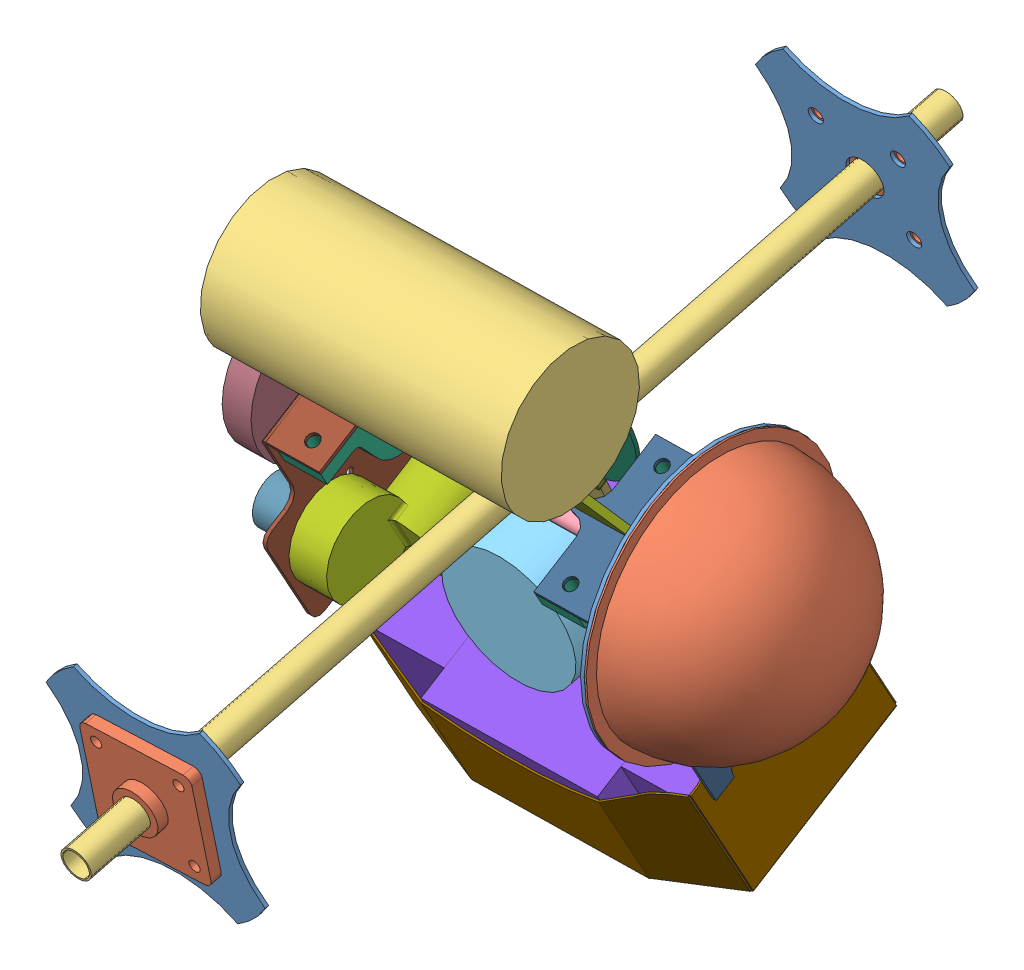
SolidWorks assembly integrated, configuration Default. Lengths in mm.
Overall size (475.58 540.92 801.49).
124 component instances, 31 part files, 95 mates.
Components (placement in the parent):
- whole_shell-1: whole_shell [Default] x (0.998835 -0.023991 -0.04186) z (0.036124 -0.203278 0.978455) size (1237.57 1237.01 762) (hidden)
  - frame1-1: frame1 [Default] x (0.840513 0.541791 0) z (-0.541791 0.840513 0) size (896.02 758.6 894.17)
    - sphere_outline-1: sphere_outline [Default] at origin size (762 758.6 762) (hidden)
    - rib-1: rib [Default] x (-1 0 0) z (0 1 0) size (381.83 596.96 365.18)
    - waist-1: waist [Default] x (-1 0 0) z (0 1 0) size (743.4 741.73 3.17)
    - axle_frame-1: axle_frame [Default] at (0 -6.0987 0) x (-1 0 0) z (0 1 0) size (203.2 203.2 44.45)
    - inside_rib-1: inside_rib [Default] x (1 0 0) z (0 1 0) size (379.15 205.09 365.17)
    - outside_rib-1: outside_rib [Default] x (1 0 0) z (0 1 0) size (373.79 201.22 360.01)
    - outside_rib-2: outside_rib [Default] x (0.809017 0 -0.587785) z (0 1 0) size (373.79 201.22 360.01)
    - outside_rib-3: outside_rib [Default] x (0.309017 0 -0.951057) z (0 1 0) size (373.79 201.22 360.01)
    - outside_rib-4: outside_rib [Default] x (-0.309017 0 -0.951057) z (0 1 0) size (373.79 201.22 360.01)
    - outside_rib-5: outside_rib [Default] x (-0.809017 0 -0.587785) z (0 1 0) size (373.79 201.22 360.01)
    - outside_rib-6: outside_rib [Default] x (-1 0 0) z (0 1 0) size (373.79 201.22 360.01)
    - outside_rib-7: outside_rib [Default] x (-0.809017 0 0.587785) z (0 1 0) size (373.79 201.22 360.01)
    - outside_rib-8: outside_rib [Default] x (-0.309017 0 0.951057) z (0 1 0) size (373.79 201.22 360.01)
    - outside_rib-9: outside_rib [Default] x (0.309017 0 0.951057) z (0 1 0) size (373.79 201.22 360.01)
    - inside_rib-2: inside_rib [Default] x (0.809017 0 -0.587785) z (0 1 0) size (379.15 205.09 365.17)
    - inside_rib-3: inside_rib [Default] x (0.309017 0 -0.951057) z (0 1 0) size (379.15 205.09 365.17)
    - inside_rib-4: inside_rib [Default] x (-0.309017 0 -0.951057) z (0 1 0) size (379.15 205.09 365.17)
    - inside_rib-5: inside_rib [Default] x (-0.809017 0 -0.587785) z (0 1 0) size (379.15 205.09 365.17)
    - inside_rib-6: inside_rib [Default] x (-1 0 0) z (0 1 0) size (379.15 205.09 365.17)
    - inside_rib-7: inside_rib [Default] x (-0.809017 0 0.587785) z (0 1 0) size (379.15 205.09 365.17)
    - inside_rib-8: inside_rib [Default] x (-0.309017 0 0.951057) z (0 1 0) size (379.15 205.09 365.17)
    - inside_rib-9: inside_rib [Default] x (0.309017 0 0.951057) z (0 1 0) size (379.15 205.09 365.17)
    - outside_rib-10: outside_rib [Default] x (0.809017 0 0.587785) z (0 1 0) size (373.79 201.22 360.01)
    - inside_rib-10: inside_rib [Default] x (0.809017 0 0.587785) z (0 1 0) size (379.15 205.09 365.17)
    - inside_rib-21: inside_rib [short] x (0.951057 0 -0.309017) z (0 1 0) size (304.88 133.31 293.67)
    - inside_rib-22: inside_rib [short] x (0.587785 0 -0.809017) z (0 1 0) size (304.88 133.31 293.67)
    - inside_rib-23: inside_rib [short] x (0 0 -1) z (0 1 0) size (304.88 133.31 293.67)
    - inside_rib-24: inside_rib [short] x (-0.587785 0 -0.809017) z (0 1 0) size (304.88 133.31 293.67)
    - inside_rib-25: inside_rib [short] x (-0.951057 0 -0.309017) z (0 1 0) size (304.88 133.31 293.67)
    - inside_rib-26: inside_rib [short] x (-0.951057 0 0.309017) z (0 1 0) size (304.88 133.31 293.67)
    - inside_rib-27: inside_rib [short] x (-0.587785 0 0.809017) z (0 1 0) size (304.88 133.31 293.67)
    - inside_rib-28: inside_rib [short] x (0 0 1) z (0 1 0) size (304.88 133.31 293.67)
    - inside_rib-29: inside_rib [short] x (0.587785 0 0.809017) z (0 1 0) size (304.88 133.31 293.67)
    - inside_rib-30: inside_rib [short] x (0.951057 0 0.309017) z (0 1 0) size (304.88 133.31 293.67)
    - outside_rib-21: outside_rib [short] x (0.951057 0 -0.309017) z (0 1 0) size (304.88 133.31 293.67)
    - outside_rib-22: outside_rib [short] x (0.587785 0 -0.809017) z (0 1 0) size (304.88 133.31 293.67)
    - outside_rib-23: outside_rib [short] x (0 0 -1) z (0 1 0) size (304.88 133.31 293.67)
    - outside_rib-24: outside_rib [short] x (-0.587785 0 -0.809017) z (0 1 0) size (304.88 133.31 293.67)
    - outside_rib-25: outside_rib [short] x (-0.951057 0 -0.309017) z (0 1 0) size (304.88 133.31 293.67)
    - outside_rib-26: outside_rib [short] x (-0.951057 0 0.309017) z (0 1 0) size (304.88 133.31 293.67)
    - outside_rib-27: outside_rib [short] x (-0.587785 0 0.809017) z (0 1 0) size (304.88 133.31 293.67)
    - outside_rib-28: outside_rib [short] x (0 0 1) z (0 1 0) size (304.88 133.31 293.67)
    - outside_rib-29: outside_rib [short] x (0.587785 0 0.809017) z (0 1 0) size (304.88 133.31 293.67)
    - outside_rib-30: outside_rib [short] x (0.951057 0 0.309017) z (0 1 0) size (304.88 133.31 293.67)
  - frame1-2: frame1 [Default] x (-0.840513 -0.541791 0) z (-0.541791 0.840513 0) size (896.02 758.6 894.17)
    - sphere_outline-1: sphere_outline [Default] at origin size (762 758.6 762) (hidden)
    - rib-1: rib [Default] x (-1 0 0) z (0 1 0) size (381.83 596.96 365.18)
    - waist-1: waist [Default] x (-1 0 0) z (0 1 0) size (743.4 741.73 3.17)
    - axle_frame-1: axle_frame [Default] at (0 -6.0987 0) x (-1 0 0) z (0 1 0) size (203.2 203.2 44.45)
    - inside_rib-1: inside_rib [Default] x (1 0 0) z (0 1 0) size (379.15 205.09 365.17)
    - outside_rib-1: outside_rib [Default] x (1 0 0) z (0 1 0) size (373.79 201.22 360.01)
    - outside_rib-2: outside_rib [Default] x (0.809017 0 -0.587785) z (0 1 0) size (373.79 201.22 360.01)
    - outside_rib-3: outside_rib [Default] x (0.309017 0 -0.951057) z (0 1 0) size (373.79 201.22 360.01)
    - outside_rib-4: outside_rib [Default] x (-0.309017 0 -0.951057) z (0 1 0) size (373.79 201.22 360.01)
    - outside_rib-5: outside_rib [Default] x (-0.809017 0 -0.587785) z (0 1 0) size (373.79 201.22 360.01)
    - outside_rib-6: outside_rib [Default] x (-1 0 0) z (0 1 0) size (373.79 201.22 360.01)
    - outside_rib-7: outside_rib [Default] x (-0.809017 0 0.587785) z (0 1 0) size (373.79 201.22 360.01)
    - outside_rib-8: outside_rib [Default] x (-0.309017 0 0.951057) z (0 1 0) size (373.79 201.22 360.01)
    - outside_rib-9: outside_rib [Default] x (0.309017 0 0.951057) z (0 1 0) size (373.79 201.22 360.01)
    - inside_rib-2: inside_rib [Default] x (0.809017 0 -0.587785) z (0 1 0) size (379.15 205.09 365.17)
    - inside_rib-3: inside_rib [Default] x (0.309017 0 -0.951057) z (0 1 0) size (379.15 205.09 365.17)
    - inside_rib-4: inside_rib [Default] x (-0.309017 0 -0.951057) z (0 1 0) size (379.15 205.09 365.17)
    - inside_rib-5: inside_rib [Default] x (-0.809017 0 -0.587785) z (0 1 0) size (379.15 205.09 365.17)
    - inside_rib-6: inside_rib [Default] x (-1 0 0) z (0 1 0) size (379.15 205.09 365.17)
    - inside_rib-7: inside_rib [Default] x (-0.809017 0 0.587785) z (0 1 0) size (379.15 205.09 365.17)
    - inside_rib-8: inside_rib [Default] x (-0.309017 0 0.951057) z (0 1 0) size (379.15 205.09 365.17)
    - inside_rib-9: inside_rib [Default] x (0.309017 0 0.951057) z (0 1 0) size (379.15 205.09 365.17)
    - outside_rib-10: outside_rib [Default] x (0.809017 0 0.587785) z (0 1 0) size (373.79 201.22 360.01)
    - inside_rib-10: inside_rib [Default] x (0.809017 0 0.587785) z (0 1 0) size (379.15 205.09 365.17)
    - inside_rib-21: inside_rib [short] x (0.951057 0 -0.309017) z (0 1 0) size (304.88 133.31 293.67)
    - inside_rib-22: inside_rib [short] x (0.587785 0 -0.809017) z (0 1 0) size (304.88 133.31 293.67)
    - inside_rib-23: inside_rib [short] x (0 0 -1) z (0 1 0) size (304.88 133.31 293.67)
    - inside_rib-24: inside_rib [short] x (-0.587785 0 -0.809017) z (0 1 0) size (304.88 133.31 293.67)
    - inside_rib-25: inside_rib [short] x (-0.951057 0 -0.309017) z (0 1 0) size (304.88 133.31 293.67)
    - inside_rib-26: inside_rib [short] x (-0.951057 0 0.309017) z (0 1 0) size (304.88 133.31 293.67)
    - inside_rib-27: inside_rib [short] x (-0.587785 0 0.809017) z (0 1 0) size (304.88 133.31 293.67)
    - inside_rib-28: inside_rib [short] x (0 0 1) z (0 1 0) size (304.88 133.31 293.67)
    - inside_rib-29: inside_rib [short] x (0.587785 0 0.809017) z (0 1 0) size (304.88 133.31 293.67)
    - inside_rib-30: inside_rib [short] x (0.951057 0 0.309017) z (0 1 0) size (304.88 133.31 293.67)
    - outside_rib-21: outside_rib [short] x (0.951057 0 -0.309017) z (0 1 0) size (304.88 133.31 293.67)
    - outside_rib-22: outside_rib [short] x (0.587785 0 -0.809017) z (0 1 0) size (304.88 133.31 293.67)
    - outside_rib-23: outside_rib [short] x (0 0 -1) z (0 1 0) size (304.88 133.31 293.67)
    - outside_rib-24: outside_rib [short] x (-0.587785 0 -0.809017) z (0 1 0) size (304.88 133.31 293.67)
    - outside_rib-25: outside_rib [short] x (-0.951057 0 -0.309017) z (0 1 0) size (304.88 133.31 293.67)
    - outside_rib-26: outside_rib [short] x (-0.951057 0 0.309017) z (0 1 0) size (304.88 133.31 293.67)
    - outside_rib-27: outside_rib [short] x (-0.587785 0 0.809017) z (0 1 0) size (304.88 133.31 293.67)
    - outside_rib-28: outside_rib [short] x (0 0 1) z (0 1 0) size (304.88 133.31 293.67)
    - outside_rib-29: outside_rib [short] x (0.587785 0 0.809017) z (0 1 0) size (304.88 133.31 293.67)
    - outside_rib-30: outside_rib [short] x (0.951057 0 0.309017) z (0 1 0) size (304.88 133.31 293.67)
- hub_flange-1: hub_flange [Default] at (-11.8884 66.8994 -322.0129) x (0.999347 0.007348 -0.035369) z (0.036124 -0.203278 0.978455) size (165.1 165.1 3.17)
- flange_bearing-1: flange_bearing [Default] at (-12.0031 67.5448 -325.1194) x (0.999347 0.007348 -0.035369) z (0 0.979094 0.20341) size (95.25 19.05 95.25)
- hub_flange-2: hub_flange [Default] at (12.0031 -67.5448 325.1194) x (0.999347 0.007348 -0.035369) z (0.036124 -0.203278 0.978455) size (165.1 165.1 3.17)
- flange_bearing-2: flange_bearing [Default] at (12.0031 -67.5448 325.1194) x (0.999347 0.007348 -0.035369) z (0 -0.979094 -0.20341) size (95.25 19.05 95.25)
- axle-1: axle [Default] x (0.998835 -0.023991 -0.04186) z (-0.031984 -0.978827 -0.202174) size (25.4 812.8 25.4)
- small_axle-1: small_axle [Default] x (-0.036124 0.203278 -0.978455) z (0.998835 -0.023991 -0.04186) size (15.88 15.88 327.03)
- drive_motor-1: drive_motor [Default] at (15.4437 -68.5896 -47.269) x (0.599108 0.788047 0.141601) z (0.036124 -0.203278 0.978455) size (112 132 107.2)
- pillow_block-1: pillow_block [Default] at (105.3435 26.4021 12.2055) x (0.024368 -0.497968 0.866853) z (0.998835 -0.023991 -0.04186) size (127 59.45 36.51)
- pillow_block-2: pillow_block [Default] at (-112.0809 31.6245 21.3176) x (0.024368 -0.497968 0.866853) z (0.998835 -0.023991 -0.04186) size (127 59.45 36.51)
- steering_motor-2: steering_motor [Default] at (-144.0481 -97.9785 15.4513) x (-0.041642 -0.866863 -0.496804) z (-0.998835 0.023991 0.04186) size (101.85 177.8 87.5)
- battery_module-2: battery_module [Default] at (-5.7974 -187.0692 -31.1163) x (0.998835 -0.023991 -0.04186) z (-0.024368 0.497968 -0.866853) size (284.35 141.22 201.17)
  - battery-1: battery [for_assembly] at origin size (149.22 101.6 66.04)
  - battery-4: battery [for_assembly] at (0 0 66.04) size (149.22 101.6 66.04)
  - battery-5: battery [for_assembly] at (0 0 132.08) size (149.22 101.6 66.04)
  - battery-8: battery [for_assembly] at (107.6325 0 66.04) x (0 0 -1) z (1 0 0) size (149.22 101.6 66.04)
  - battery-9: battery [for_assembly] at (-107.6325 0 66.04) x (0 0 1) z (-1 0 0) size (149.22 101.6 66.04)
  - battery_tray-1: battery_tray [Default] at (0 101.6 66.04) x (-1 0 0) z (0 1 0) size (284.35 201.17 141.22)
- tray_bracket-1: tray_bracket [Default] at (105.3435 26.4021 12.2055) x (-0.998835 0.023991 0.04186) z (0.024368 -0.497968 0.866853) size (78.58 215.9 127)
- steering_bracket-3: steering_bracket [Default] at (-112.0809 31.6245 21.3176) x (-0.998835 0.023991 0.04186) z (0.024368 -0.497968 0.866853) size (69.06 215.9 165.1)
- motor_plate-1: motor_plate [Default] at (15.4437 -68.5896 -47.269) x (-0.599108 -0.788047 -0.141601) z (-0.036124 0.203278 -0.978455) size (138.65 111.84 6.35)
- driveshaft-1: driveshaft [Default] at (-11.8884 66.8994 -322.0129) x (0.999347 0.007348 -0.035369) z (0.036124 -0.203278 0.978455) size (38.1 38.1 279.4) (hidden)
- tsprock_40-1: tsprock_40 [Default] at (-164.3369 3.9473 6.8872) x (0.041034 -0.033955 0.998581) z (-0.998835 0.023991 0.04186) size (121.29 121.29 24.38)
- tsprock_10-1: tsprock_10 [Default] at (-166.3741 -97.4423 16.3869) x (-0.047046 -0.676787 -0.734674) z (-0.998835 0.023991 0.04186) size (41.68 41.68 24.38)
- cog_27t-1: cog_27t [Default] at (-2.5088 14.1176 -67.9537) x (0.99934 0.003712 -0.036124) z (0.036124 -0.203278 0.978455) size (88.9 88.9 3.17)
- bh_front-1: bh_front [Default] x (-0.036124 0.203278 -0.978455) z (0.994465 0.103976 -0.015113) size (822.32 411.16 9.53) (hidden)
- bh_back-1: bh_back [Default] x (-0.036124 0.203278 -0.978455) z (0.986115 -0.151549 -0.067891) size (822.32 411.16 9.53) (hidden)
- bh_pod-1: bh_pod [Default] at (12.9982 397.7954 82.1636) x (-0.999488 0.031323 0.00647) z (0.031984 0.978827 0.202174) size (127 127 25.4) (hidden)
- crossmember-1: crossmember [Default] at (105.3435 26.4021 12.2055) x (-0.998835 0.023991 0.04186) z (0.024368 -0.497968 0.866853) size (252.6 74.61 6.35)
- pot_holder-1: pot_holder [Default] at (146.5705 25.4119 10.4777) x (0.024368 -0.497968 0.866853) z (0.998835 -0.023991 -0.04186) size (50.8 44.45 1.59)
- potentiometer-1: potentiometer [Default] at (160.7216 -3.8604 -6.7357) x (0.024368 -0.497968 0.866853) z (-0.998835 0.023991 0.04186) size (26.42 26.42 39.37)
- acetal-1: acetal [Default] at (146.5705 25.4119 10.4777) x (0.024368 -0.497968 0.866853) z (0.998835 -0.023991 -0.04186) size (231.78 231.78 3.18)
- dome-1: dome [Default] at (146.5705 25.4119 10.4777) x (-0.998835 0.023991 0.04186) z (0.024368 -0.497968 0.866853) size (107.95 231.78 231.78)
- speakertube-1: speakertube [Default] at (7.404 154.1283 88.3317) x (0.024368 -0.497968 0.866853) z (-0.998835 0.023991 0.04186) size (127 127 254)
Mates (geometry in assembly coordinates):
- InPlace1: in place: plane of ?
- Coincident1: coincident aligned: plane of ?; plane of assembly
- Coincident2: coincident aligned: plane of ?; moOrthogonalPlaneRef_w of assembly
- Coincident3: coincident anti-aligned: plane of ?; moOrthogonalPlaneRef_w of assembly
- Coincident4: coincident anti-aligned: plane of ? through (-12.0031 140.1446 -310.0366) normal (-0.036124 0.203278 -0.978455); plane of flange_bearing-1 through (-59.5971 113.8242 -313.7476) normal (0.036124 -0.203278 0.978455)
- Coincident8: coincident aligned: plane of ? through (-11.8884 66.8994 -322.0129) normal (0 0.979094 0.20341); plane of flange_bearing-1 through (-12.0031 67.5448 -325.1194) normal (0 0.979094 0.20341)
- Coincident9: coincident aligned: plane of ? through (-11.8884 66.8994 -322.0129) normal (0.999347 0.007348 -0.035369); plane of flange_bearing-1 through (-12.0031 67.5448 -325.1194) normal (0.999347 0.007348 -0.035369)
- Coincident10: coincident anti-aligned: plane of hub_flange-2 through (12.0031 5.055 340.2023) normal (0.036124 -0.203278 0.978455); plane of flange_bearing-2 through (-35.5908 -114.5241 317.1165) normal (-0.036124 0.203278 -0.978455)
- Coincident11: coincident aligned: plane of flange_bearing-1 through (-12.0031 67.5448 -325.1194) normal (0.999347 0.007348 -0.035369); plane of flange_bearing-2 through (12.0031 -67.5448 325.1194) normal (0.999347 0.007348 -0.035369)
- Coincident12: coincident anti-aligned: plane of flange_bearing-1 through (-12.0031 67.5448 -325.1194) normal (0 0.979094 0.20341); plane of flange_bearing-2 through (12.0031 -67.5448 325.1194) normal (0 -0.979094 -0.20341)
- Concentric1: concentric anti-aligned: cylinder of flange_bearing-2; cylinder of axle-1
- Coincident13: coincident aligned: plane of whole_shell-1 through (0 0 0) normal (0.036124 -0.203278 0.978455); plane of axle-1 through (0 0 0) normal (0.036124 -0.203278 0.978455)
- InPlace2: in place: unknown of whole_shell-1; unknown of small_axle-1
- Coincident14: coincident aligned: plane of ?; plane of ?
- Coincident15: coincident aligned: moOrthogonalPlaneRef_w of ?; plane of ?
- Coincident16: coincident anti-aligned: moOrthogonalPlaneRef_w of ?; plane of ?
- Coincident19: coincident anti-aligned: plane of whole_shell-1 through (0 0 0) normal (0.036124 -0.203278 0.978455); plane of drive_motor-1 through (16.5906 -75.0437 -16.2031) normal (-0.036124 0.203278 -0.978455)
- Distance1: distance = 19.05 mm anti-aligned: plane of whole_shell-1 through (0 0 0) normal (0.998835 -0.023991 -0.04186); plane of drive_motor-1 through (15.4437 -68.5896 -47.269) normal (-0.998835 0.023991 0.04186)
- Coincident21: coincident aligned: plane of ? through (-11.8884 66.8994 -322.0129) normal (0 0.979094 0.20341); plane of hub_flange-2 through (12.0031 -67.5448 325.1194) normal (0 0.979094 0.20341)
- Coincident22: coincident aligned: plane of ? through (-11.8884 66.8994 -322.0129) normal (0.999347 0.007348 -0.035369); plane of hub_flange-2 through (12.0031 -67.5448 325.1194) normal (0.999347 0.007348 -0.035369)
- Distance2: distance = 6.35 mm aligned: plane of whole_shell-1/frame1-2/axle_frame-1 through (11.6591 -65.6086 315.7997) normal (-0.036124 0.203278 -0.978455); plane of hub_flange-2 through (11.8884 5.7004 337.0957) normal (-0.036124 0.203278 -0.978455)
- Concentric3: concentric anti-aligned: cylinder of small_axle-1; cylinder of pillow_block-1
- Concentric4: concentric anti-aligned: cylinder of small_axle-1; cylinder of pillow_block-2
- Coincident23: coincident aligned: plane of pillow_block-1 through (122.0311 57.5851 -43.6039) normal (0.041642 0.866863 0.496804); plane of pillow_block-2 through (-95.3933 62.8075 -34.4917) normal (0.041642 0.866863 0.496804)
- InPlace4: in place: unknown of pillow_block-2; unknown of steering_bracket-3
- Coincident30: coincident aligned: plane of ?; plane of ?
- Coincident31: coincident aligned: moOrthogonalPlaneRef_w of ?; plane of ?
- Coincident32: coincident anti-aligned: moOrthogonalPlaneRef_w of ?; plane of ?
- Coincident33: coincident anti-aligned: plane of steering_bracket-3 through (-138.213 -19.6597 109.7973) normal (0.998835 -0.023991 -0.04186); plane of steering_motor-2 through (-144.0481 -97.9785 15.4513) normal (-0.998835 0.023991 0.04186)
- Distance6: distance = 101.854 mm: line of small_axle-1; line of steering_motor-2
- InPlace5: in place: unknown of pillow_block-1; unknown of ?
- Coincident36: coincident aligned: plane of ?; plane of ?
- Coincident37: coincident aligned: moOrthogonalPlaneRef_w of ?; plane of ?
- Coincident38: coincident anti-aligned: moOrthogonalPlaneRef_w of ?; plane of ?
- InPlace7: in place: unknown of drive_motor-1; unknown of motor_plate-1
- Coincident42: coincident aligned: plane of ?; plane of ?
- Coincident43: coincident aligned: moOrthogonalPlaneRef_w of ?; plane of ?
- Coincident44: coincident anti-aligned: moOrthogonalPlaneRef_w of ?; plane of ?
- InPlace9: in place: unknown of ?; unknown of ?
- Coincident48: coincident aligned: plane of ?; plane of ?
- Coincident49: coincident aligned: moOrthogonalPlaneRef_w of ?; plane of ?
- Coincident50: coincident anti-aligned: moOrthogonalPlaneRef_w of ?; plane of ?
- Concentric5: concentric anti-aligned: cylinder of small_axle-1; cylinder of tsprock_40-1
- Concentric6: concentric aligned: cylinder of steering_motor-2; cylinder of tsprock_10-1
- Coincident36: coincident aligned: plane of tsprock_10-1 through (-190.7297 -96.8573 17.4077) normal (-0.998835 0.023991 0.04186); plane of tsprock_40-1 through (-188.6925 4.5323 7.908) normal (-0.998835 0.023991 0.04186)
- Concentric7: concentric aligned: cylinder of ?; cylinder of cog_27t-1
- Coincident37: coincident aligned: plane of drive_motor-1 through (42.8766 -81.8451 -89.5659) normal (-0.036124 0.203278 -0.978455); plane of cog_27t-1 through (-2.5088 14.1176 -67.9537) normal (-0.036124 0.203278 -0.978455)
- InPlace10: in place: unknown of whole_shell-1; unknown of bh_front-1
- Coincident38: coincident aligned: plane of ?; plane of ?
- Coincident39: coincident aligned: moOrthogonalPlaneRef_w of ?; plane of ?
- Coincident40: coincident anti-aligned: moOrthogonalPlaneRef_w of ?; plane of ?
- InPlace11: in place: unknown of whole_shell-1; unknown of bh_back-1
- Coincident41: coincident aligned: plane of ?; plane of ?
- Coincident42: coincident aligned: moOrthogonalPlaneRef_w of ?; plane of ?
- Coincident43: coincident anti-aligned: moOrthogonalPlaneRef_w of ?; plane of ?
- InPlace12: in place: unknown of bh_pod-1
- Coincident44: coincident aligned: plane of ?; plane of assembly
- Coincident45: coincident aligned: plane of ?; moOrthogonalPlaneRef_w of assembly
- Coincident46: coincident anti-aligned: plane of ?; moOrthogonalPlaneRef_w of assembly
- Distance7: distance = 76.2 mm: plane of whole_shell-1 through (0 0 0) normal (0.031984 0.978827 0.202174); line of drive_motor-1
- Parallel1: parallel aligned: plane of steering_bracket-3 through (-112.0809 31.6245 21.3176) normal (-0.041642 -0.866863 -0.496804); plane of steering_motor-2 through (-144.0481 -97.9785 15.4513) normal (-0.041642 -0.866863 -0.496804)
- Coincident41: coincident aligned: plane of steering_bracket-3 through (-112.0809 31.6245 21.3176) normal (0.024368 -0.497968 0.866853); plane of steering_motor-2 through (-145.4779 -68.7607 -35.4104) normal (0.024368 -0.497968 0.866853)
- Coincident42: coincident anti-aligned: plane of axle-1 through (0 0 0) normal (-0.031984 -0.978827 -0.202174); plane of small_axle-1 through (0 0 0) normal (0.031984 0.978827 0.202174)
- Coincident43: coincident aligned: plane of axle-1 through (0 0 0) normal (0.998835 -0.023991 -0.04186); plane of battery_module-2/battery-1 through (-5.7974 -187.0692 -31.1163) normal (0.998835 -0.023991 -0.04186)
- Distance8: distance = 317.5 mm anti-aligned: plane of steering_bracket-3 through (-91.2379 -16.6548 110.203) normal (0.041642 0.866863 0.496804); plane of battery_module-2/battery_tray-1 through (126.3738 -197.6234 -231.3539) normal (-0.041642 -0.866863 -0.496804)
- Coincident45: coincident anti-aligned: plane of ? through (105.3435 26.4021 12.2055) normal (0.024368 -0.497968 0.866853); plane of battery_module-2/battery_tray-1 through (-11.6375 -242.2566 -138.8386) normal (-0.024368 0.497968 -0.866853)
- Coincident48: coincident anti-aligned: plane of ? through (141.5456 -302.06 154.111) normal (-0.998835 0.023991 0.04186); plane of battery_module-2/battery_tray-1 through (134.3727 -87.4122 -140.0647) normal (0.998835 -0.023991 -0.04186)
- Coincident50: coincident anti-aligned: plane of steering_bracket-3 through (-138.213 -19.6597 109.7973) normal (0.998835 -0.023991 -0.04186); plane of battery_module-2/battery_tray-1 through (-146.0128 -154.8995 1.1946) normal (-0.998835 0.023991 0.04186)
- InPlace13: in place: unknown of ?; unknown of ?
- Coincident51: coincident aligned: plane of ?; plane of ?
- Coincident52: coincident aligned: moOrthogonalPlaneRef_w of ?; plane of ?
- Coincident53: coincident anti-aligned: moOrthogonalPlaneRef_w of ?; plane of ?
- InPlace14: in place: unknown of ?; unknown of ?
- Coincident51: coincident aligned: plane of ?; plane of ?
- Coincident52: coincident aligned: moOrthogonalPlaneRef_w of ?; plane of ?
- Coincident53: coincident anti-aligned: moOrthogonalPlaneRef_w of ?; plane of ?
- Concentric8: concentric aligned: circle of ?; cylinder of potentiometer-1
- Coincident54: coincident anti-aligned: plane of ? through (148.3123 3.0924 26.9086) normal (0.998835 -0.023991 -0.04186); plane of potentiometer-1 through (146.7679 -3.5253 -6.1509) normal (-0.998835 0.023991 0.04186)
- InPlace15: in place: unknown of ?; unknown of ?
- Coincident55: coincident aligned: plane of ?; plane of ?
- Coincident56: coincident aligned: moOrthogonalPlaneRef_w of ?; plane of ?
- Coincident57: coincident anti-aligned: moOrthogonalPlaneRef_w of ?; plane of ?
- Distance9: distance = 46.736 mm anti-aligned: plane of steering_bracket-3 through (-138.213 -19.6597 109.7973) normal (0.998835 -0.023991 -0.04186); plane of tsprock_40-1 through (-188.6925 4.5323 7.908) normal (-0.998835 0.023991 0.04186)
- InPlace16: in place: unknown of ?; unknown of dome-1
- Coincident55: coincident aligned: plane of ?; plane of ?
- Coincident56: coincident aligned: moOrthogonalPlaneRef_w of ?; plane of ?
- Coincident57: coincident anti-aligned: moOrthogonalPlaneRef_w of ?; plane of ?
- Parallel2: parallel aligned: plane of ? through (94.2456 -113.5522 263.73) normal (0.041642 0.866863 0.496804); plane of potentiometer-1 through (160.7216 -3.8604 -6.7357) normal (0.041642 0.866863 0.496804)
- Coincident59: coincident anti-aligned: plane of small_axle-1 through (0 0 0) normal (0.998835 -0.023991 -0.04186); plane of speakertube-1 through (7.404 154.1283 88.3317) normal (-0.998835 0.023991 0.04186)
- Distance10: distance = 177.8 mm: line of small_axle-1; line of speakertube-1
- Coincident61: coincident aligned: unknown of ?; unknown of speakertube-1
- PLANE1: unknown = 6.35 mm: unknown of whole_shell-1/frame1-1/axle_frame-1
- bh_pod: unknown = 406.4 mm: unknown of whole_shell-1
- Axis2: unknown: unknown of motor_plate-1
- Axis3: unknown: unknown of drive_motor-1
